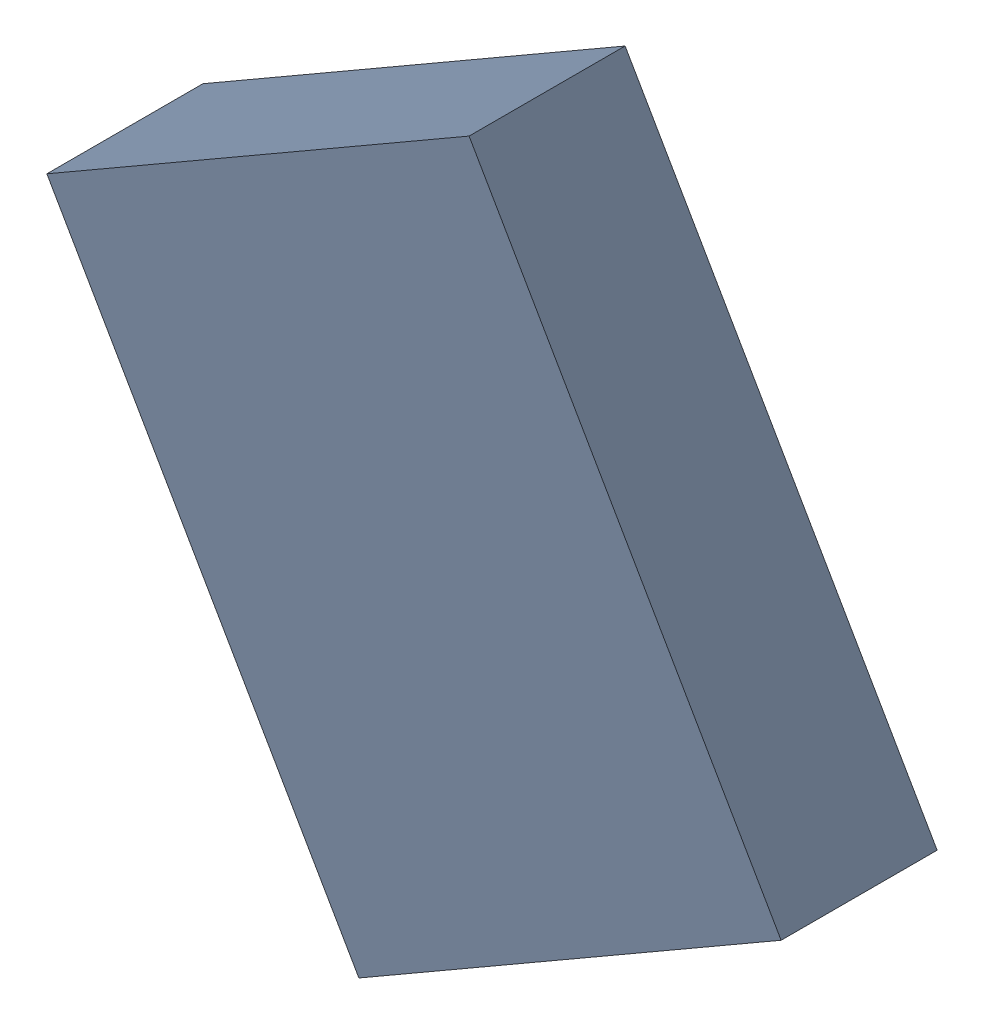
SolidWorks assembly X_TDA_1_TDA5, configuration Standard. Lengths in mm.
Overall size (3.77 4.02 0.8).
2 component instances, 1 part files, 0 mates.
Components (placement in the parent):
- 668293664-1: 668293664 [Standard] at (-34.8042 -23.4933 0) size (3.77 4.02 0.8)
  - Extruded_2-1: Extruded_2 [Standard] at origin size (3.77 4.02 0.8)
